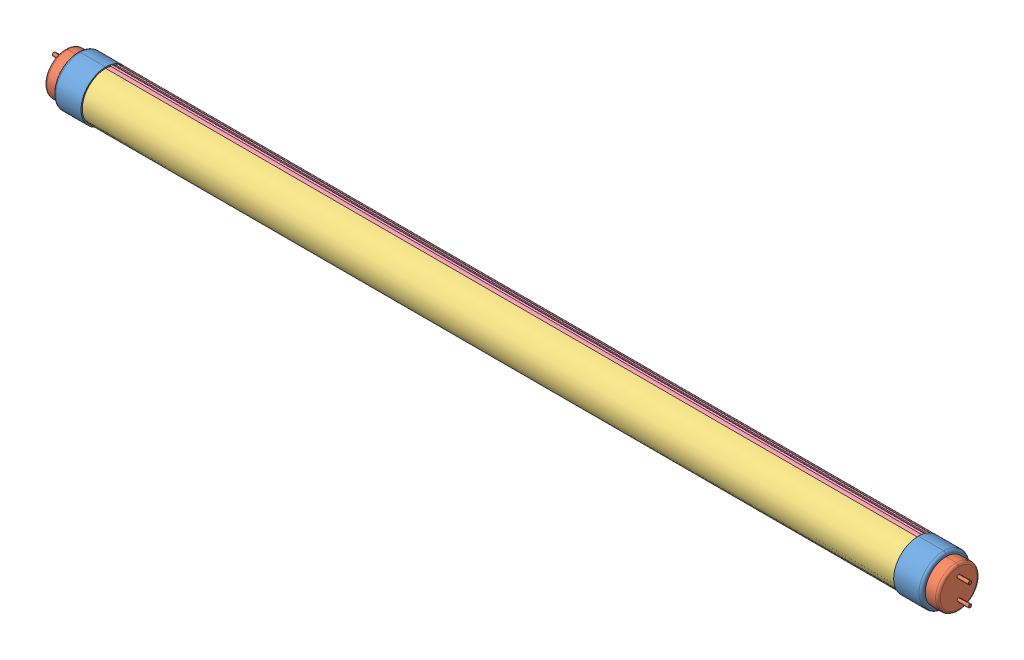
SolidWorks assembly TubeLight, configuration Default. Lengths in mm.
Overall size (561.11 36.96 30.18).
28 component instances, 7 part files, 0 mates.
Components (placement in the parent):
- Final assembly of tubelight.stp-1: Final assembly of tubelight.stp [Default] at origin size (561.11 30.18 30.18)
  - Product1.1.stp-1: Product1.1.stp [Default] at origin size (31.75 30.18 30.18)
    - Part1.stp-1: Part1.stp [Default] at origin size (17 30.18 30.18)
    - Part2.stp-1: Part2.stp [Default] x (-1 0 0) z (0 0 1) size (14.75 25.4 25.4)
  - Product1.1.stp-2: Product1.1.stp [Default] at (531.6091 0 0) x (-1 0 0) z (0 0 1) size (31.75 30.18 30.18)
    - Part1.stp-1: Part1.stp [Default] at origin size (17 30.18 30.18)
    - Part2.stp-1: Part2.stp [Default] x (-1 0 0) z (0 0 1) size (14.75 25.4 25.4)
  - Part3.stp-1: Part3.stp [Default] at origin size (528 28.68 14.34)
  - glass back part metal.stp-1: glass back part metal.stp [Default] at (514.6091 -0.0125 0) x (1 0 0) z (0 0 -1) size (497.61 29.11 14.98)
  - Led strip.stp-1: Led strip.stp [Default] at origin size (528 28.07 1)
  - LED.stp-1: LED.stp [Default] at (407.649 45.3125 -26.9011) x (1 0 0) z (0 -1 0) size (6.01 23.55 6.01)
  - LED.stp-2: LED.stp [Default] at (449.1358 38.3368 -26.9011) x (1 0 0) z (0 -1 0) size (6.01 23.55 6.01)
  - LED.stp-3: LED.stp [Default] at (449.1212 52.3743 -26.9011) x (1 0 0) z (0 -1 0) size (6.01 23.55 6.01)
  - LED.stp-4: LED.stp [Default] at (366.1621 38.3368 -26.9011) x (1 0 0) z (0 -1 0) size (6.01 23.55 6.01)
  - LED.stp-5: LED.stp [Default] at (366.1767 52.3743 -26.9011) x (1 0 0) z (0 -1 0) size (6.01 23.55 6.01)
  - LED.stp-6: LED.stp [Default] at (324.719 45.3125 -26.9011) x (1 0 0) z (0 -1 0) size (6.01 23.55 6.01)
  - LED.stp-7: LED.stp [Default] at (283.2759 38.3368 -26.9011) x (1 0 0) z (0 -1 0) size (6.01 23.55 6.01)
  - LED.stp-8: LED.stp [Default] at (283.2613 52.3743 -26.9011) x (1 0 0) z (0 -1 0) size (6.01 23.55 6.01)
  - LED.stp-9: LED.stp [Default] at (241.7891 45.3125 -26.9011) x (1 0 0) z (0 -1 0) size (6.01 23.55 6.01)
  - LED.stp-10: LED.stp [Default] at (200.3241 38.2937 -26.9011) x (1 0 0) z (0 -1 0) size (6.01 23.55 6.01)
  - LED.stp-11: LED.stp [Default] at (200.3241 52.3312 -26.9011) x (1 0 0) z (0 -1 0) size (6.01 23.55 6.01)
  - LED.stp-12: LED.stp [Default] at (158.8591 45.3125 -26.9011) x (1 0 0) z (0 -1 0) size (6.01 23.55 6.01)
  - LED.stp-13: LED.stp [Default] at (117.3941 38.2937 -26.9011) x (1 0 0) z (0 -1 0) size (6.01 23.55 6.01)
  - LED.stp-14: LED.stp [Default] at (117.3941 52.3312 -26.9011) x (1 0 0) z (0 -1 0) size (6.01 23.55 6.01)
  - LED.stp-15: LED.stp [Default] at (75.9291 45.3125 -26.9011) x (1 0 0) z (0 -1 0) size (6.01 23.55 6.01)
  - LED.stp-16: LED.stp [Default] at (34.4641 38.2937 -26.9011) x (1 0 0) z (0 -1 0) size (6.01 23.55 6.01)
  - LED.stp-17: LED.stp [Default] at (34.4641 52.3312 -26.9011) x (1 0 0) z (0 -1 0) size (6.01 23.55 6.01)
  - led part assembly.CATPart-1: led part assembly.CATPart [Default] at (18.2413 0 -2.1948) (suppressed, hidden)
